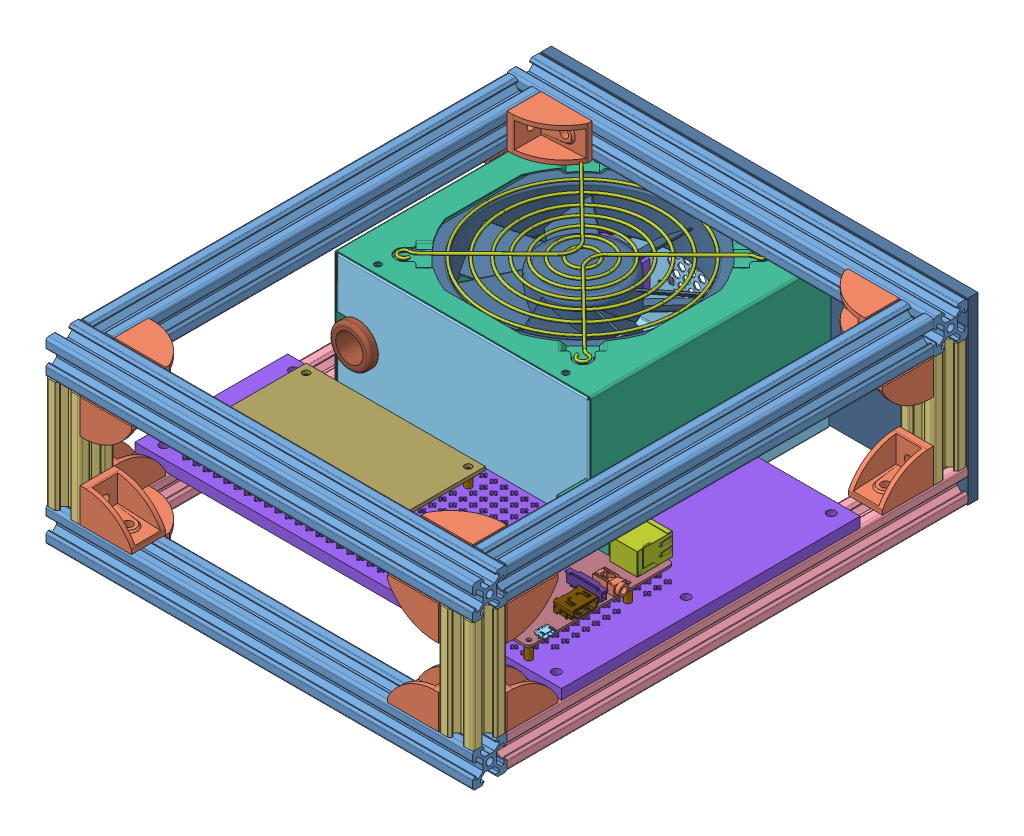
SolidWorks assembly Frame Base, configuration Default. Lengths in mm.
Overall size (250 105.4 296).
64 component instances, 28 part files, 118 mates.
Components (placement in the parent):
- Frame-1: Frame [Default] at (15.0219 -51.4444 -34.8708) size (20 20 250)
- Frame-2: Frame [Default] at (255.0219 -51.4444 -44.8708) x (0 0 1) z (-1 0 0) size (20 20 250)
- Frame-3: Frame [Default] at (245.0219 -51.4444 -34.8708) size (20 20 250)
- Frame-4: Frame [Default] at (255.0219 -51.4444 225.1292) x (0 0 1) z (-1 0 0) size (20 20 250)
- Misumi L bracket-1: Misumi L bracket [Default] at (235.0219 -61.4444 -34.8708) x (0 1 0) z (0 0 1) size (20 31 21)
- Misumi L bracket-2: Misumi L bracket [Default] at (235.0219 -41.4444 215.1292) x (0 -1 0) z (0 0 -1) size (20 31 21)
- Misumi L bracket-3: Misumi L bracket [Default] at (25.0219 -41.4444 -34.8708) x (0 -1 0) z (0 0 1) size (20 31 21)
- Misumi L bracket-4: Misumi L bracket [Default] at (25.0219 -61.4444 215.1292) x (0 1 0) z (0 0 -1) size (20 31 21)
- Base Supports-1: Base Supports [Default] at (15.0219 -126.4444 225.1292) x (1 0 0) z (0 1 0) size (20 20 65)
- Base Supports-2: Base Supports [Default] at (15.0219 -126.4444 -44.8708) x (1 0 0) z (0 1 0) size (20 20 65)
- Base Supports-3: Base Supports [Default] at (245.0219 -126.4444 225.1292) x (1 0 0) z (0 1 0) size (20 20 65)
- Base Supports-4: Base Supports [Default] at (245.0219 -61.4444 -44.8708) x (1 0 0) z (0 -1 0) size (20 20 65)
- Frame-5: Frame [Default] at (255.0219 -136.4444 225.1292) x (0 0 1) z (-1 0 0) size (20 20 250)
- Frame Long-1: Frame Long [Default] at (245.0219 -136.4444 -54.8708) size (20 20 270)
- Frame Long-2: Frame Long [Default] at (15.0219 -136.4444 -54.8708) size (20 20 270)
- ATX Power Supply v1.0-1: ATX Power Supply v1.0 [Default] at (100.0219 -146.8444 15.6292) x (-1 0 0) z (0 0 -1) size (150 86.42 152)
  - Box v1.0 - ATX Power Supply-1: Box v1.0 - ATX Power Supply [Default] at origin size (150 84.7 141.01)
  - Cover v1.0 - ATX Power Supply-1: Cover v1.0 - ATX Power Supply [Default] at (0 2.9 0) size (150 82.63 140.5)
  - Grelha Prot Vent 120-1: Grelha Prot Vent 120 [Default] at (0 85.55 0) x (-1 0 0) z (0 -1 0) size (115.85 114.72 3.29)
  - IEC Plug-1: IEC Plug [Default] at (44.5 24 70.5) size (49.54 22 31)
  - Switch on-off-1: Switch on-off [Default] at (36 54.5 62.5) x (0 -1 0) z (0 0 1) size (15 21 21.45)
  - Ventax 119x119x26-1: Ventax 119x119x26 [Default] at (0 60.95 0) x (1 0 0) z (0 -1 0) size (124.36 129.72 26)
  - Casq-1: Casq [Default] at (61.3 45 -58.5) x (1 0 0) z (0 1 0) size (24 17 24)
- Misumi L bracket-5: Misumi L bracket [Default] at (25.0219 -146.4444 215.1292) x (0 1 0) z (0 0 -1) size (20 31 21)
- Misumi L bracket-6: Misumi L bracket [Default] at (235.0219 -126.4444 215.1292) x (1 0 0) z (0 1 0) size (20 31 21)
- Misumi L bracket-7: Misumi L bracket [Default] at (235.0219 -126.4444 215.1292) x (0 -1 0) z (0 0 -1) size (20 31 21)
- Misumi L bracket-8: Misumi L bracket [Default] at (235.0219 -61.4444 -34.8708) x (1 0 0) z (0 -1 0) size (20 31 21)
- Misumi L bracket-9: Misumi L bracket [Default] at (255.0219 -126.4444 -34.8708) x (-1 0 0) z (0 1 0) size (20 31 21)
- Misumi L bracket-10: Misumi L bracket [Default] at (25.0219 -61.4444 215.1292) x (-1 0 0) z (0 -1 0) size (20 31 21)
- Misumi L bracket-11: Misumi L bracket [Default] at (25.0219 -126.4444 -34.8708) x (-1 0 0) z (0 1 0) size (20 31 21)
- Misumi L bracket-12: Misumi L bracket [Default] at (5.0219 -61.4444 -34.8708) x (1 0 0) z (0 -1 0) size (20 31 21)
- Misumi L bracket-13: Misumi L bracket [Default] at (5.0219 -126.4444 215.1292) x (1 0 0) z (0 1 0) size (20 31 21)
- Misumi L bracket-14: Misumi L bracket [Default] at (25.0219 -61.4444 235.1292) x (0 0 -1) z (0 -1 0) size (20 31 21)
- Misumi L bracket-15: Misumi L bracket [Default] at (255.0219 -61.4444 215.1292) x (-1 0 0) z (0 -1 0) size (20 31 21)
- Misumi L bracket-16: Misumi L bracket [Default] at (235.0219 -61.4444 215.1292) x (0 0 1) z (0 -1 0) size (20 31 21)
- Misumi L bracket-17: Misumi L bracket [Default] at (235.0219 -126.4444 235.1292) x (0 0 -1) z (0 1 0) size (20 31 21)
- Misumi L bracket-18: Misumi L bracket [Default] at (25.0219 -126.4444 215.1292) x (0 0 1) z (0 1 0) size (20 31 21)
- MiniRambo-1: MiniRambo [Default] at (77.5224 -112.4444 138.2459) size (105 2 71)
- RaspberryPi2 model B SW-1: RaspberryPi2 model B SW [Default] at (205.5219 -111.1444 138.2459) x (0 0 -1) z (1 0 0) size (89.62 18.75 58.3)
  - Mainboard2-1: Mainboard2 [Default] at origin size (85 1.3 56)
  - GPIO-1: GPIO [Default] at (-11.37 0 -24.5) x (0 0 1) z (-1 0 0) size (5 11.5 50.8)
  - Processor-1: Processor [Default] at (-15.5 0 -3) x (0 0 1) z (-1 0 0) size (14 1 14)
  - GPU-1: GPU [Default] at (15.25 0 -5.75) x (0 0 1) z (-1 0 0) size (9.1 1 9.1)
  - CameraAssembly-4: CameraAssembly [Default] at (10.0885 -2.9159 16.55) x (-1 0 0) z (0 0 -1) size (5 5.5 22.1)
  - CameraAssembly-3: CameraAssembly [Default] at (-46.3885 -2.9159 0) size (5 5.5 22.1)
  - hdmi-1: hdmi [Default] at (-10.2 0.27 29.3) size (15.14 8.38 12.15)
  - RAM-1: RAM [Default] at (0.5 -2.3 -6) x (0 0 1) z (-1 0 0) size (12 1 12)
  - Audio-1: Audio [Default] at (10.9 0.15 21.75) size (7 6 14.8)
  - MicroSDSocket-1: MicroSDSocket [Default] at (-34.5 -1.3 -0.7) x (0 0 -1) z (-1 0 0) size (13 1.3 14)
  - MicroSD-1: MicroSD [Default] at (-37 -2.3 0.1) x (0 0 1) z (-1 0 0) size (11 1 15)
  - micro USB2-1: micro USB2 [Default] at (-17.2704 -5.0969 44.9026) size (7.99 2.94 5.43)
  - usb double-1: usb double [Default] at (30.38 -0.09 -18.85) x (0 0 -1) z (1 0 0) size (15.6 18.75 17.92)
  - usb double-2: usb double [Default] at (30.38 -0.09 -1.25) x (0 0 -1) z (1 0 0) size (15.6 18.75 17.92)
  - RJ45-LED-1: RJ45-LED [Default] at (34.11 7.4 17.348) x (1 0 0) z (0 -1 0) size (20.75 17.99 14.09)
- Electronics Platform-1: Electronics Platform [Default] at (129.698 -120.4444 138.2459) x (-1 0 0) z (0 0 1) size (250 6 175)
- M3 Spacer-1: M3 Spacer [Default] at (230.0219 -120.4444 177.2459) x (0.996702 0 0.081143) z (-0.081143 0 0.996702) size (4 8 4)
- M3 Spacer-2: M3 Spacer [Default] at (181.0219 -120.4444 119.2459) x (0.707838 0 0.706374) z (-0.706374 0 0.707838) size (4 8 4)
- M3 Spacer-3: M3 Spacer [Default] at (230.0219 -120.4444 119.2459) x (0.665006 0 -0.746838) z (0.746838 0 0.665006) size (4 8 4)
- M3 Spacer-4: M3 Spacer [Default] at (181.0219 -120.4444 177.2459) x (0.824752 0 0.565494) z (-0.565494 0 0.824752) size (4 8 4)
- M3 Spacer-5: M3 Spacer [Default] at (125.0224 -120.4444 107.7459) x (0.921904 0 -0.387417) z (0.387417 0 0.921904) size (4 8 4)
- M3 Spacer-6: M3 Spacer [Default] at (125.0224 -120.4444 168.7459) x (0.747282 0 -0.664507) z (0.664507 0 0.747282) size (4 8 4)
- M3 Spacer-7: M3 Spacer [Default] at (30.0224 -120.4444 107.7459) x (0.861641 0 -0.507518) z (0.507518 0 0.861641) size (4 8 4)
- M3 Spacer-8: M3 Spacer [Default] at (30.0224 -120.4444 168.7459) x (-0.841758 0 -0.539856) z (0.539856 0 -0.841758) size (4 8 4)
- PSU Plate-1: PSU Plate [Default] at (130.0219 -93.9444 -54.8708) x (-1 0 0) z (0 -1 0) size (250 6 105)
Mates (geometry in assembly coordinates):
- Coincident1: coincident anti-aligned: plane of Frame-1 through (24.3308 -46.5816 215.1292) normal (0 0 1); plane of Frame-4 through (5.0219 -42.9444 215.1292) normal (0 0 -1)
- Coincident2: coincident aligned: plane of Frame-1 through (19.8847 -41.4444 215.1292) normal (0 1 0); plane of Frame-4 through (5.0219 -41.4444 216.6292) normal (0 1 0)
- Coincident3: coincident aligned: plane of Frame-1 through (5.0219 -42.9444 215.1292) normal (-1 0 0); plane of Frame-4 through (5.0219 -46.5816 234.438) normal (-1 0 0)
- Coincident4: coincident aligned: plane of Frame-3 through (255.0219 -42.9444 215.1292) normal (1 0 0); plane of Frame-4 through (255.0219 -46.5816 234.438) normal (1 0 0)
- Coincident5: coincident aligned: plane of Frame-3 through (236.5219 -41.4444 215.1292) normal (0 1 0); plane of Frame-4 through (5.0219 -41.4444 216.6292) normal (0 1 0)
- Coincident6: coincident anti-aligned: plane of Frame-3 through (254.3308 -46.5816 215.1292) normal (0 0 1); plane of Frame-4 through (5.0219 -42.9444 215.1292) normal (0 0 -1)
- Coincident7: coincident anti-aligned: plane of Frame-1 through (24.3308 -46.5816 -34.8708) normal (0 0 -1); plane of Frame-2 through (5.0219 -42.9444 -34.8708) normal (0 0 1)
- Coincident8: coincident: plane of Frame-1 through (5.0219 -42.9444 215.1292) normal (-1 0 0); point of Frame-2
- Coincident9: coincident aligned: plane of Frame-1 through (6.5219 -41.4444 215.1292) normal (0 1 0); plane of Frame-2 through (5.0219 -41.4444 -40.008) normal (0 1 0)
- Coincident10: coincident aligned: plane of Frame-2 through (5.0219 -41.4444 -40.008) normal (0 1 0); plane of Frame-3 through (249.8847 -41.4444 215.1292) normal (0 1 0)
- Coincident11: coincident anti-aligned: plane of Frame-4 through (5.0219 -42.9444 215.1292) normal (0 0 -1); plane of Misumi L bracket-4 through (25.0219 -61.4444 215.1292) normal (0 0 1)
- Coincident12: coincident aligned: plane of Frame-4 through (5.0219 -41.4444 216.6292) normal (0 1 0); plane of Misumi L bracket-4 through (26.4319 -41.4444 227.0592) normal (0 1 0)
- Coincident13: coincident anti-aligned: plane of Frame-1 through (25.0219 -42.9444 215.1292) normal (1 0 0); plane of Misumi L bracket-4 through (25.0219 -61.4444 215.1292) normal (-1 0 0)
- Coincident14: coincident anti-aligned: plane of Frame-2 through (5.0219 -42.9444 -34.8708) normal (0 0 1); plane of Misumi L bracket-3 through (25.0219 -41.4444 -34.8708) normal (0 0 -1)
- Coincident15: coincident aligned: plane of Frame-2 through (5.0219 -41.4444 -40.008) normal (0 1 0); plane of Misumi L bracket-3 through (26.4319 -41.4444 -46.8008) normal (0 1 0)
- Coincident16: coincident anti-aligned: plane of Frame-1 through (25.0219 -42.9444 215.1292) normal (1 0 0); plane of Misumi L bracket-3 through (25.0219 -41.4444 -34.8708) normal (-1 0 0)
- Coincident17: coincident anti-aligned: plane of Frame-4 through (5.0219 -42.9444 215.1292) normal (0 0 -1); plane of Misumi L bracket-2 through (235.0219 -41.4444 215.1292) normal (0 0 1)
- Coincident18: coincident aligned: plane of Frame-4 through (5.0219 -41.4444 216.6292) normal (0 1 0); plane of Misumi L bracket-2 through (233.6119 -41.4444 227.0592) normal (0 1 0)
- Coincident19: coincident anti-aligned: plane of Frame-3 through (235.0219 -42.9444 215.1292) normal (-1 0 0); plane of Misumi L bracket-2 through (235.0219 -41.4444 215.1292) normal (1 0 0)
- Coincident20: coincident anti-aligned: plane of Frame-2 through (5.0219 -42.9444 -34.8708) normal (0 0 1); plane of Misumi L bracket-1 through (235.0219 -61.4444 -34.8708) normal (0 0 -1)
- Coincident22: coincident anti-aligned: plane of Frame-3 through (235.0219 -42.9444 215.1292) normal (-1 0 0); plane of Misumi L bracket-1 through (235.0219 -61.4444 -34.8708) normal (1 0 0)
- Coincident24: coincident aligned: plane of Frame-3 through (236.5219 -41.4444 215.1292) normal (0 1 0); plane of Misumi L bracket-1 through (233.6119 -41.4444 -46.8008) normal (0 1 0)
- Coincident25: coincident anti-aligned: plane of Frame-4 through (5.0219 -61.4444 229.992) normal (0 -1 0); plane of Base Supports-1 through (24.3308 -61.4444 220.2664) normal (0 1 0)
- Coincident26: coincident aligned: plane of Frame-4 through (5.0219 -56.3072 235.1292) normal (0 0 1); plane of Base Supports-1 through (6.5219 -61.4444 235.1292) normal (0 0 1)
- Coincident27: coincident aligned: plane of Frame-4 through (5.0219 -46.5816 234.438) normal (-1 0 0); plane of Base Supports-1 through (5.0219 -61.4444 229.992) normal (-1 0 0)
- Coincident28: coincident anti-aligned: plane of Frame-4 through (5.0219 -61.4444 229.992) normal (0 -1 0); plane of Base Supports-3 through (254.3308 -61.4444 220.2664) normal (0 1 0)
- Coincident29: coincident aligned: plane of Frame-3 through (255.0219 -56.3072 215.1292) normal (1 0 0); plane of Base Supports-3 through (255.0219 -61.4444 229.992) normal (1 0 0)
- Coincident30: coincident aligned: plane of Frame-4 through (5.0219 -56.3072 235.1292) normal (0 0 1); plane of Base Supports-3 through (249.8847 -61.4444 235.1292) normal (0 0 1)
- Coincident31: coincident anti-aligned: plane of Frame-1 through (6.5219 -61.4444 215.1292) normal (0 -1 0); plane of Base Supports-2 through (24.3308 -61.4444 -49.7336) normal (0 1 0)
- Coincident32: coincident aligned: plane of Frame-2 through (5.0219 -42.9444 -54.8708) normal (0 0 -1); plane of Base Supports-2 through (6.5219 -61.4444 -54.8708) normal (0 0 -1)
- Coincident33: coincident aligned: plane of Frame-2 through (5.0219 -46.5816 -35.562) normal (-1 0 0); plane of Base Supports-2 through (5.0219 -61.4444 -53.3708) normal (-1 0 0)
- Coincident34: coincident anti-aligned: plane of Frame-2 through (5.0219 -61.4444 -53.3708) normal (0 -1 0); plane of Base Supports-4 through (254.3308 -61.4444 -40.008) normal (0 1 0)
- Coincident35: coincident aligned: plane of Frame-2 through (5.0219 -42.9444 -54.8708) normal (0 0 -1); plane of Base Supports-4 through (249.8847 -126.4444 -54.8708) normal (0 0 -1)
- Coincident36: coincident aligned: plane of Frame-3 through (255.0219 -56.3072 215.1292) normal (1 0 0); plane of Base Supports-4 through (255.0219 -126.4444 -49.7336) normal (1 0 0)
- Coincident37: coincident anti-aligned: plane of Base Supports-1 through (24.3308 -126.4444 220.2664) normal (0 -1 0); plane of Frame-5 through (5.0219 -126.4444 229.992) normal (0 1 0)
- Coincident38: coincident aligned: plane of Base Supports-1 through (19.8847 -61.4444 235.1292) normal (0 0 1); plane of Frame-5 through (5.0219 -127.9444 235.1292) normal (0 0 1)
- Coincident39: coincident aligned: plane of Base Supports-1 through (5.0219 -61.4444 229.992) normal (-1 0 0); plane of Frame-5 through (5.0219 -131.5816 234.438) normal (-1 0 0)
- Coincident43: coincident aligned: plane of Frame-5 through (255.0219 -131.5816 234.438) normal (1 0 0); plane of Frame Long-1 through (255.0219 -127.9444 215.1292) normal (1 0 0)
- Coincident44: coincident aligned: plane of Frame-5 through (5.0219 -146.4444 216.6292) normal (0 -1 0); plane of Frame Long-1 through (249.8847 -146.4444 215.1292) normal (0 -1 0)
- Coincident45: coincident anti-aligned: plane of Frame-5 through (5.0219 -127.9444 215.1292) normal (0 0 -1); plane of Frame Long-1 through (254.3308 -131.5816 215.1292) normal (0 0 1)
- Coincident46: coincident aligned: plane of Frame-5 through (5.0219 -131.5816 234.438) normal (-1 0 0); plane of Frame Long-2 through (5.0219 -127.9444 215.1292) normal (-1 0 0)
- Coincident47: coincident anti-aligned: plane of Frame-5 through (5.0219 -127.9444 215.1292) normal (0 0 -1); plane of Frame Long-2 through (24.3308 -131.5816 215.1292) normal (0 0 1)
- Coincident48: coincident aligned: plane of Frame-5 through (5.0219 -146.4444 229.992) normal (0 -1 0); plane of Frame Long-2 through (6.5219 -146.4444 215.1292) normal (0 -1 0)
- Coincident49: coincident aligned: plane of Frame-2 through (5.0219 -42.9444 -54.8708) normal (0 0 -1); plane of ATX Power Supply v1.0-1/Box v1.0 - ATX Power Supply-1 through (173.0219 -145.6444 -54.8708) normal (0 0 -1)
- Coincident50: coincident anti-aligned: plane of Frame-2 through (5.0219 -61.4444 -53.3708) normal (0 -1 0); plane of ATX Power Supply v1.0-1/Cover v1.0 - ATX Power Supply-1 through (173.8219 -61.4444 85.8792) normal (0 1 0)
- Coincident52: coincident anti-aligned: plane of Frame-5 through (5.0219 -127.9444 215.1292) normal (0 0 -1); plane of Misumi L bracket-7 through (235.0219 -126.4444 215.1292) normal (0 0 1)
- Coincident53: coincident aligned: plane of Frame-5 through (5.0219 -126.4444 216.6292) normal (0 1 0); plane of Misumi L bracket-7 through (233.6119 -126.4444 227.0592) normal (0 1 0)
- Coincident54: coincident anti-aligned: plane of Frame Long-1 through (235.0219 -127.9444 215.1292) normal (-1 0 0); plane of Misumi L bracket-7 through (235.0219 -126.4444 215.1292) normal (1 0 0)
- Coincident55: coincident anti-aligned: plane of Frame-5 through (5.0219 -127.9444 215.1292) normal (0 0 -1); plane of Misumi L bracket-5 through (25.0219 -146.4444 215.1292) normal (0 0 1)
- Coincident57: coincident anti-aligned: plane of Frame Long-2 through (25.0219 -127.9444 215.1292) normal (1 0 0); plane of Misumi L bracket-5 through (25.0219 -146.4444 215.1292) normal (-1 0 0)
- Coincident58: coincident aligned: plane of Frame-5 through (5.0219 -126.4444 216.6292) normal (0 1 0); plane of Misumi L bracket-5 through (26.4319 -126.4444 227.0592) normal (0 1 0)
- Coincident62: coincident anti-aligned: plane of Base Supports-4 through (249.8847 -126.4444 -34.8708) normal (0 0 1); plane of Misumi L bracket-8 through (235.0219 -61.4444 -34.8708) normal (0 0 -1)
- Coincident63: coincident anti-aligned: plane of Frame-3 through (249.8847 -61.4444 215.1292) normal (0 -1 0); plane of Misumi L bracket-8 through (235.0219 -61.4444 -34.8708) normal (0 1 0)
- Coincident64: coincident aligned: plane of Frame-3 through (255.0219 -56.3072 215.1292) normal (1 0 0); plane of Misumi L bracket-8 through (255.0219 -49.5144 -33.4608) normal (1 0 0)
- Coincident65: coincident anti-aligned: plane of Frame Long-1 through (249.8847 -126.4444 215.1292) normal (0 1 0); plane of Misumi L bracket-9 through (255.0219 -126.4444 -34.8708) normal (0 -1 0)
- Coincident66: coincident anti-aligned: plane of Base Supports-4 through (249.8847 -126.4444 -34.8708) normal (0 0 1); plane of Misumi L bracket-9 through (255.0219 -126.4444 -34.8708) normal (0 0 -1)
- Coincident68: coincident aligned: plane of Base Supports-4 through (255.0219 -126.4444 -36.3708) normal (1 0 0); plane of Misumi L bracket-9 through (255.0219 -138.3744 -33.4608) normal (1 0 0)
- Coincident69: coincident aligned: plane of Frame Long-1 through (255.0219 -141.3072 215.1292) normal (1 0 0); plane of Misumi L bracket-6 through (255.0219 -138.3744 213.7192) normal (1 0 0)
- Coincident70: coincident anti-aligned: plane of Base Supports-3 through (249.8847 -61.4444 215.1292) normal (0 0 -1); plane of Misumi L bracket-6 through (235.0219 -126.4444 215.1292) normal (0 0 1)
- Coincident71: coincident anti-aligned: plane of Frame Long-1 through (249.8847 -126.4444 215.1292) normal (0 1 0); plane of Misumi L bracket-6 through (235.0219 -126.4444 215.1292) normal (0 -1 0)
- Coincident72: coincident anti-aligned: plane of Base Supports-3 through (249.8847 -61.4444 215.1292) normal (0 0 -1); plane of Misumi L bracket-15 through (255.0219 -61.4444 215.1292) normal (0 0 1)
- Coincident73: coincident anti-aligned: plane of Frame-3 through (249.8847 -61.4444 215.1292) normal (0 -1 0); plane of Misumi L bracket-15 through (255.0219 -61.4444 215.1292) normal (0 1 0)
- Coincident74: coincident aligned: plane of Frame-3 through (255.0219 -42.9444 215.1292) normal (1 0 0); plane of Misumi L bracket-15 through (255.0219 -49.5144 213.7192) normal (1 0 0)
- Coincident75: coincident aligned: plane of Frame Long-2 through (5.0219 -127.9444 215.1292) normal (-1 0 0); plane of Misumi L bracket-13 through (5.0219 -138.3744 213.7192) normal (-1 0 0)
- Coincident76: coincident anti-aligned: plane of Frame Long-2 through (6.5219 -126.4444 215.1292) normal (0 1 0); plane of Misumi L bracket-13 through (5.0219 -126.4444 215.1292) normal (0 -1 0)
- Coincident77: coincident anti-aligned: plane of Base Supports-1 through (6.5219 -61.4444 215.1292) normal (0 0 -1); plane of Misumi L bracket-13 through (5.0219 -126.4444 215.1292) normal (0 0 1)
- Coincident78: coincident aligned: plane of Frame-1 through (5.0219 -56.3072 215.1292) normal (-1 0 0); plane of Misumi L bracket-12 through (5.0219 -49.5144 -33.4608) normal (-1 0 0)
- Coincident79: coincident anti-aligned: plane of Frame-1 through (6.5219 -61.4444 215.1292) normal (0 -1 0); plane of Misumi L bracket-12 through (5.0219 -61.4444 -34.8708) normal (0 1 0)
- Coincident80: coincident anti-aligned: plane of Base Supports-2 through (19.8847 -61.4444 -34.8708) normal (0 0 1); plane of Misumi L bracket-12 through (5.0219 -61.4444 -34.8708) normal (0 0 -1)
- Coincident81: coincident anti-aligned: plane of Frame Long-2 through (6.5219 -126.4444 215.1292) normal (0 1 0); plane of Misumi L bracket-11 through (25.0219 -126.4444 -34.8708) normal (0 -1 0)
- Coincident82: coincident anti-aligned: plane of Base Supports-2 through (19.8847 -61.4444 -34.8708) normal (0 0 1); plane of Misumi L bracket-11 through (25.0219 -126.4444 -34.8708) normal (0 0 -1)
- Coincident84: coincident aligned: plane of Base Supports-2 through (5.0219 -61.4444 -40.008) normal (-1 0 0); plane of Misumi L bracket-11 through (5.0219 -138.3744 -33.4608) normal (-1 0 0)
- Coincident85: coincident anti-aligned: plane of Frame-1 through (6.5219 -61.4444 215.1292) normal (0 -1 0); plane of Misumi L bracket-10 through (25.0219 -61.4444 215.1292) normal (0 1 0)
- Coincident86: coincident anti-aligned: plane of Base Supports-1 through (6.5219 -61.4444 215.1292) normal (0 0 -1); plane of Misumi L bracket-10 through (25.0219 -61.4444 215.1292) normal (0 0 1)
- Coincident87: coincident aligned: plane of Frame-1 through (5.0219 -56.3072 215.1292) normal (-1 0 0); plane of Misumi L bracket-10 through (5.0219 -49.5144 213.7192) normal (-1 0 0)
- Coincident88: coincident aligned: plane of Frame-4 through (5.0219 -56.3072 235.1292) normal (0 0 1); plane of Misumi L bracket-14 through (26.4319 -49.5144 235.1292) normal (0 0 1)
- Coincident89: coincident anti-aligned: plane of Frame-4 through (5.0219 -61.4444 229.992) normal (0 -1 0); plane of Misumi L bracket-14 through (25.0219 -61.4444 235.1292) normal (0 1 0)
- Coincident90: coincident anti-aligned: plane of Base Supports-1 through (25.0219 -61.4444 229.992) normal (1 0 0); plane of Misumi L bracket-14 through (25.0219 -61.4444 235.1292) normal (-1 0 0)
- Coincident91: coincident aligned: plane of Frame-4 through (5.0219 -56.3072 235.1292) normal (0 0 1); plane of Misumi L bracket-16 through (233.6119 -49.5144 235.1292) normal (0 0 1)
- Coincident92: coincident anti-aligned: plane of Frame-4 through (5.0219 -61.4444 229.992) normal (0 -1 0); plane of Misumi L bracket-16 through (235.0219 -61.4444 215.1292) normal (0 1 0)
- Coincident93: coincident anti-aligned: plane of Base Supports-3 through (235.0219 -61.4444 229.992) normal (-1 0 0); plane of Misumi L bracket-16 through (235.0219 -61.4444 215.1292) normal (1 0 0)
- Coincident94: coincident aligned: plane of Frame-5 through (5.0219 -127.9444 235.1292) normal (0 0 1); plane of Misumi L bracket-17 through (233.6119 -138.3744 235.1292) normal (0 0 1)
- Coincident95: coincident anti-aligned: plane of Frame-5 through (5.0219 -126.4444 229.992) normal (0 1 0); plane of Misumi L bracket-17 through (235.0219 -126.4444 235.1292) normal (0 -1 0)
- Coincident96: coincident anti-aligned: plane of Base Supports-3 through (235.0219 -61.4444 229.992) normal (-1 0 0); plane of Misumi L bracket-17 through (235.0219 -126.4444 235.1292) normal (1 0 0)
- Coincident97: coincident aligned: plane of Frame-5 through (5.0219 -127.9444 235.1292) normal (0 0 1); plane of Misumi L bracket-18 through (26.4319 -138.3744 235.1292) normal (0 0 1)
- Coincident98: coincident anti-aligned: plane of Frame-5 through (5.0219 -126.4444 229.992) normal (0 1 0); plane of Misumi L bracket-18 through (25.0219 -126.4444 215.1292) normal (0 -1 0)
- Coincident99: coincident anti-aligned: plane of Base Supports-1 through (25.0219 -61.4444 229.992) normal (1 0 0); plane of Misumi L bracket-18 through (25.0219 -126.4444 215.1292) normal (-1 0 0)
- Concentric11: concentric aligned: cylinder of MiniRambo-1 through (30.0224 -110.4444 107.7459) axis (0 -1 0) radius 2; cylinder of M3 Spacer-7 through (30.0224 -112.4444 107.7459) axis (0 -1 0) radius 1.5
- Concentric12: concentric aligned: cylinder of MiniRambo-1 through (125.0224 -110.4444 168.7459) axis (0 -1 0) radius 2; cylinder of M3 Spacer-6 through (125.0224 -112.4444 168.7459) axis (0 -1 0) radius 1.5
- Coincident114: coincident anti-aligned: plane of MiniRambo-1 through (77.5224 -112.4444 138.2459) normal (0 -1 0); plane of M3 Spacer-6 through (125.0224 -112.4444 168.7459) normal (0 1 0)
- Concentric13: concentric anti-aligned: cylinder of RaspberryPi2 model B SW-1/Mainboard2-1 through (181.0219 -112.4444 177.2459) axis (0 1 0) radius 1.25; cylinder of M3 Spacer-4 through (181.0219 -112.4444 177.2459) axis (0 -1 0) radius 1.5
- Concentric14: concentric anti-aligned: cylinder of RaspberryPi2 model B SW-1/Mainboard2-1 through (230.0219 -112.4444 119.2459) axis (0 1 0) radius 1.25; cylinder of M3 Spacer-3 through (230.0219 -112.4444 119.2459) axis (0 -1 0) radius 1.5
- Coincident115: coincident anti-aligned: plane of RaspberryPi2 model B SW-1/Mainboard2-1 through (231.0219 -112.4444 98.2459) normal (0 -1 0); plane of M3 Spacer-4 through (181.0219 -112.4444 177.2459) normal (0 1 0)
- Distance1: distance = 2 mm anti-aligned: plane of Electronics Platform-1 through (255.0219 -126.4444 183.1292) normal (0 0 1); plane of Misumi L bracket-13 through (25.0219 -126.4444 185.1292) normal (0 0 -1)
- Concentric23: concentric aligned: cylinder of MiniRambo-1 through (125.0224 -110.4444 107.7459) axis (0 -1 0) radius 2; cylinder of M3 Spacer-5 through (125.0224 -112.4444 107.7459) axis (0 -1 0) radius 1.5
- Concentric24: concentric aligned: cylinder of MiniRambo-1 through (30.0224 -110.4444 168.7459) axis (0 -1 0) radius 2; cylinder of M3 Spacer-8 through (30.0224 -112.4444 168.7459) axis (0 -1 0) radius 1.5
- Coincident126: coincident anti-aligned: plane of Base Supports-2 through (25.0219 -61.4444 -53.3708) normal (1 0 0); plane of ATX Power Supply v1.0-1/Cover v1.0 - ATX Power Supply-1 through (25.0219 -137.4473 -54.6208) normal (-1 0 0)
- Concentric25: concentric anti-aligned: cylinder of RaspberryPi2 model B SW-1/Mainboard2-1 through (230.0219 -112.4444 177.2459) axis (0 1 0) radius 1.25; cylinder of M3 Spacer-1 through (230.0219 -112.4444 177.2459) axis (0 -1 0) radius 1.5
- Concentric26: concentric anti-aligned: cylinder of RaspberryPi2 model B SW-1/Mainboard2-1 through (230.0219 -112.4444 119.2459) axis (0 1 0) radius 1.25; cylinder of M3 Spacer-3 through (230.0219 -112.4444 119.2459) axis (0 -1 0) radius 1.5
- Concentric27: concentric anti-aligned: cylinder of RaspberryPi2 model B SW-1/Mainboard2-1 through (181.0219 -112.4444 119.2459) axis (0 1 0) radius 1.25; cylinder of M3 Spacer-2 through (181.0219 -112.4444 119.2459) axis (0 -1 0) radius 1.5
- Concentric28: concentric anti-aligned: cylinder of RaspberryPi2 model B SW-1/Mainboard2-1 through (181.0219 -112.4444 177.2459) axis (0 1 0) radius 1.25; cylinder of M3 Spacer-4 through (181.0219 -112.4444 177.2459) axis (0 -1 0) radius 1.5
- Coincident127: coincident anti-aligned: plane of RaspberryPi2 model B SW-1/Mainboard2-1 through (231.0219 -112.4444 98.2459) normal (0 -1 0); plane of M3 Spacer-1 through (230.0219 -112.4444 177.2459) normal (0 1 0)
- Coincident128: coincident anti-aligned: plane of RaspberryPi2 model B SW-1/Mainboard2-1 through (231.0219 -112.4444 98.2459) normal (0 -1 0); plane of M3 Spacer-3 through (230.0219 -112.4444 119.2459) normal (0 1 0)
- Coincident129: coincident anti-aligned: plane of RaspberryPi2 model B SW-1/Mainboard2-1 through (231.0219 -112.4444 98.2459) normal (0 -1 0); plane of M3 Spacer-2 through (181.0219 -112.4444 119.2459) normal (0 1 0)
- Coincident130: coincident anti-aligned: plane of MiniRambo-1 through (77.5224 -112.4444 138.2459) normal (0 -1 0); plane of M3 Spacer-5 through (125.0224 -112.4444 107.7459) normal (0 1 0)
- Coincident131: coincident anti-aligned: plane of MiniRambo-1 through (77.5224 -112.4444 138.2459) normal (0 -1 0); plane of M3 Spacer-7 through (30.0224 -112.4444 107.7459) normal (0 1 0)
- Coincident132: coincident anti-aligned: plane of MiniRambo-1 through (77.5224 -112.4444 138.2459) normal (0 -1 0); plane of M3 Spacer-8 through (30.0224 -112.4444 168.7459) normal (0 1 0)
- Coincident133: coincident anti-aligned: plane of Frame Long-1 through (249.8847 -126.4444 215.1292) normal (0 1 0); plane of Electronics Platform-1 through (129.698 -126.4444 138.2459) normal (0 -1 0)
- Coincident134: coincident aligned: plane of Frame Long-1 through (255.0219 -127.9444 215.1292) normal (1 0 0); plane of Electronics Platform-1 through (255.0219 -126.4444 93.1292) normal (1 0 0)
- Concentric29: concentric anti-aligned: cylinder of Electronics Platform-1 through (125.0224 -126.4444 107.7459) axis (0 1 0) radius 1.5; cylinder of M3 Spacer-5 through (125.0224 -112.4444 107.7459) axis (0 -1 0) radius 1.5
- Concentric30: concentric anti-aligned: cylinder of Electronics Platform-1 through (30.0224 -126.4444 168.7459) axis (0 1 0) radius 1.5; cylinder of M3 Spacer-8 through (30.0224 -112.4444 168.7459) axis (0 -1 0) radius 1.5
- Coincident135: coincident anti-aligned: plane of Electronics Platform-1 through (129.698 -120.4444 138.2459) normal (0 1 0); plane of M3 Spacer-8 through (30.0224 -120.4444 168.7459) normal (0 -1 0)
- Concentric31: concentric anti-aligned: cylinder of Electronics Platform-1 through (230.0219 -126.4444 177.2459) axis (0 1 0) radius 1.5; cylinder of M3 Spacer-1 through (230.0219 -112.4444 177.2459) axis (0 -1 0) radius 1.5
- Concentric32: concentric anti-aligned: cylinder of Electronics Platform-1 through (181.0219 -126.4444 119.2459) axis (0 1 0) radius 1.5; cylinder of M3 Spacer-2 through (181.0219 -112.4444 119.2459) axis (0 -1 0) radius 1.5
- Coincident136: coincident anti-aligned: plane of Electronics Platform-1 through (129.698 -120.4444 138.2459) normal (0 1 0); plane of M3 Spacer-3 through (230.0219 -120.4444 119.2459) normal (0 -1 0)
- Coincident138: coincident aligned: plane of Frame-2 through (5.0219 -41.4444 -53.3708) normal (0 1 0); plane of PSU Plate-1 through (255.0219 -41.4444 -60.8708) normal (0 1 0)
- Coincident140: coincident anti-aligned: plane of Frame-2 through (5.0219 -56.3072 -54.8708) normal (0 0 -1); plane of PSU Plate-1 through (130.0219 -93.9444 -54.8708) normal (0 0 1)
- Coincident141: coincident aligned: plane of Base Supports-4 through (255.0219 -126.4444 -49.7336) normal (1 0 0); plane of PSU Plate-1 through (255.0219 -146.4444 -60.8708) normal (1 0 0)
